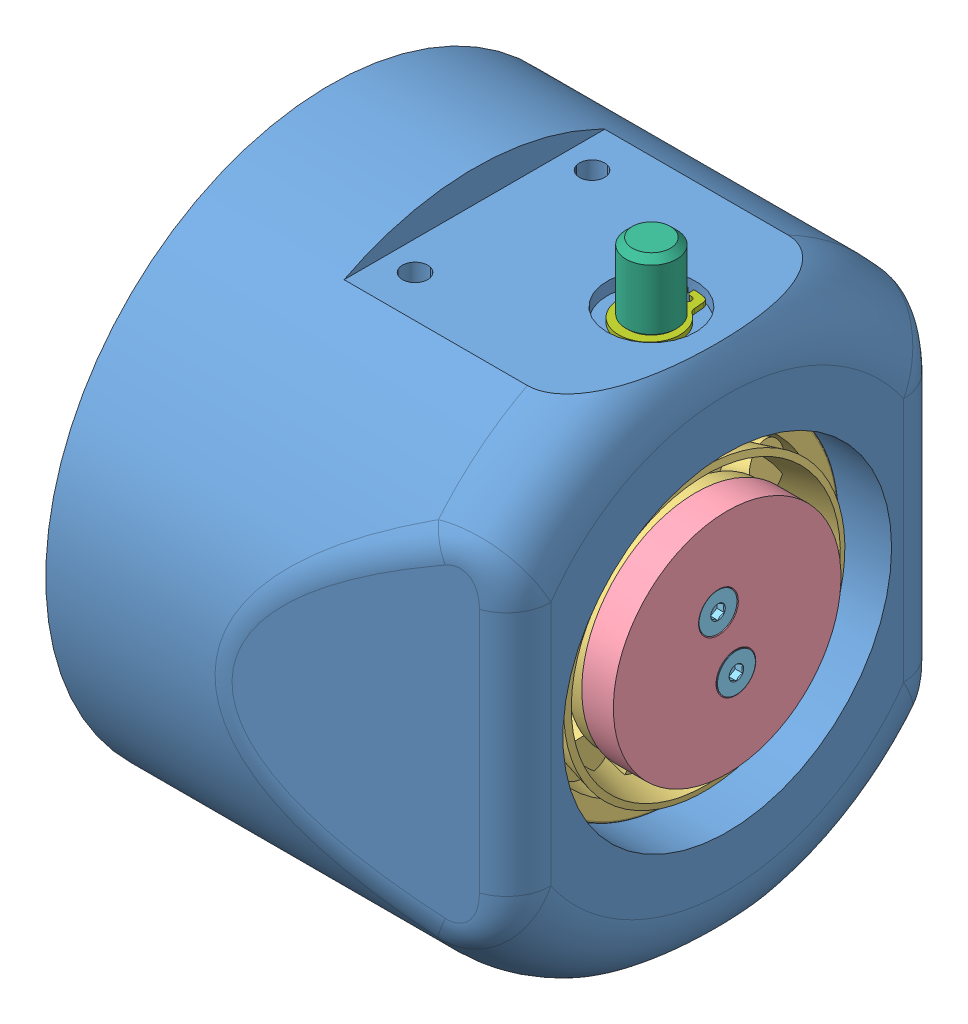
SolidWorks assembly RotationUnit, configuration Default. Lengths in mm.
Overall size (79.33 94.5 90).
9 component instances, 7 part files, 15 mates.
Components (placement in the parent):
- rotatingPart^RotationUnit-1: rotatingPart^RotationUnit [Default] at origin size (63.63 90 90) (virtual)
- Copy of axis^RotationUnit-1: Copy of axis^RotationUnit [Default] at (-47.25 0 0) x (1 0 0) z (0 -0.2761 0.961129) size (73 36 36) (virtual)
- 6677K87_Tapered-Roller Bearing with Steel Ring-1: 6677K87_Tapered-Roller Bearing with Steel Ring [6677K87] at (16.5 0 0) x (0 0.225972 0.974134) z (-1 0 0) size (52 52 19.81)
- 6677K87_Tapered-Roller Bearing with Steel Ring-2: 6677K87_Tapered-Roller Bearing with Steel Ring [6677K87] at (-16.5 0 0) x (0 0 1) z (1 0 0) size (52 52 19.81)
- Part1^RotationUnit-1: Part1^RotationUnit [Default] at (26.25 0 0) x (0 -0.2761 0.961129) z (0 0.961129 0.2761) size (36 5 36) (virtual)
- 92125A130_18-8 Stainless Steel Hex Drive Flat Head Screw-1: 92125A130_18-8 Stainless Steel Hex Drive Flat Head Screw [92125A130] at (26.335 -4.8056 -1.3805) x (0 0 -1) z (1 0 0) size (6 6 10.3)
- 92125A130_18-8 Stainless Steel Hex Drive Flat Head Screw-2: 92125A130_18-8 Stainless Steel Hex Drive Flat Head Screw [92125A130] at (26.185 4.8056 1.3805) x (0 0 -1) z (1 0 0) size (6 6 10.3)
- Part2^RotationUnit-1: Part2^RotationUnit [Default] at (19.2645 38.5 0) x (0 -1 0) z (0 0 1) size (22 8 8) (virtual)
- 90154A137_External Retaining Ring-1: 90154A137_External Retaining Ring [90154A137] at (19.2645 38.375 0) x (0.995938 0 -0.090045) z (0 -1 0) size (9.68 12.1 0.75)
Mates (geometry in assembly coordinates):
- Concentric9: concentric anti-aligned: cylinder of 6677K87_Tapered-Roller Bearing with Steel Ring-1 through (11.25 0 0) axis (-1 0 0) radius 10; cylinder of 6677K87_Tapered-Roller Bearing with Steel Ring-2 through (-11.25 0 0) axis (1 0 0) radius 10
- Concentric13: concentric anti-aligned: cylinder of rotatingPart^Assem1_Wrist-Rev1-1 through (0 0 0) axis (1 0 0) radius 26; cylinder of 6677K87_Tapered-Roller Bearing with Steel Ring-1 through (11.25 0 0) axis (-1 0 0) radius 26
- Coincident12: coincident anti-aligned: plane of rotatingPart^Assem1_Wrist-Rev1-1 through (10 19 0) normal (1 0 0); plane of 6677K87_Tapered-Roller Bearing with Steel Ring-1 through (10 19.093 -4.429) normal (-1 0 0)
- Coincident13: coincident anti-aligned: plane of rotatingPart^Assem1_Wrist-Rev1-1 through (-10 19 0) normal (-1 0 0); plane of 6677K87_Tapered-Roller Bearing with Steel Ring-2 through (-10 -19.6 0) normal (1 0 0)
- Concentric14: concentric anti-aligned: cylinder of 6677K87_Tapered-Roller Bearing with Steel Ring-2 through (-11.25 0 0) axis (1 0 0) radius 10; cylinder of Copy of axis^RotationUnit_Wrist-Rev1-1 through (-47.25 0 0) axis (-1 0 0) radius 10
- Coincident14: coincident anti-aligned: plane of 6677K87_Tapered-Roller Bearing with Steel Ring-2 through (-26.25 -10 0) normal (-1 0 0); plane of Copy of axis^RotationUnit_Wrist-Rev1-1 through (-26.25 0 0) normal (1 0 0)
- Coincident15: coincident anti-aligned: plane of 6677K87_Tapered-Roller Bearing with Steel Ring-1 through (26.25 9.7413 -2.2597) normal (1 0 0); plane of Part1^RotationUnit_Wrist-Rev1-1 through (26.25 0 0) normal (-1 0 0)
- Concentric15: concentric aligned: cylinder of 6677K87_Tapered-Roller Bearing with Steel Ring-1 through (11.25 0 0) axis (-1 0 0) radius 17.5184; cylinder of Part1^RotationUnit_Wrist-Rev1-1 through (31.25 0 0) axis (-1 0 0) radius 18
- Concentric16: concentric aligned: cone of Part1^RotationUnit_Wrist-Rev1-1 through (31.25 -4.8056 -1.3805) axis (-1 0 0); cone of 92125A130_18-8 Stainless Steel Hex Drive Flat Head Screw-1 through (31.25 -4.8056 -1.3805) axis (-1 0 0)
- Coincident17: coincident aligned: cone of Part1^RotationUnit_Wrist-Rev1-1 through (31.25 4.8056 1.3805) axis (-1 0 0); cone of 92125A130_18-8 Stainless Steel Hex Drive Flat Head Screw-2 through (31.1 4.8056 1.3805) axis (-1 0 0)
- Concentric17: concentric aligned: cylinder of Copy of axis^RotationUnit_Wrist-Rev1-1 through (25.75 -4.8056 -1.3805) axis (1 0 0) radius 1.25; cylinder of Part1^RotationUnit_Wrist-Rev1-1 through (31.25 -4.8056 -1.3805) axis (1 0 0) radius 1.6
- Concentric18: concentric anti-aligned: cylinder of rotatingPart^Assem1_Wrist-Rev1-1 through (19.2645 40 0) axis (0 1 0) radius 4; cylinder of Part2^RotationUnit_Wrist-Rev1-1 through (19.2645 27.5 0) axis (0 -1 0) radius 4
- Concentric19: concentric anti-aligned: cylinder of Part2^RotationUnit_Wrist-Rev1-1 through (19.2645 27.5 0) axis (0 -1 0) radius 3.75; cylinder of 90154A137_External Retaining Ring-1 through (19.2645 38 0) axis (0 1 0) radius 3.7
- Coincident18: coincident anti-aligned: plane of Part2^RotationUnit_Wrist-Rev1-1 through (23.0145 38 0) normal (0 1 0); plane of 90154A137_External Retaining Ring-1 through (19.2968 38 0.3571) normal (0 -1 0)
- Coincident19: coincident anti-aligned: plane of rotatingPart^Assem1_Wrist-Rev1-1 through (23.2645 38 0) normal (0 1 0); plane of 90154A137_External Retaining Ring-1 through (19.2968 38 0.3571) normal (0 -1 0)
